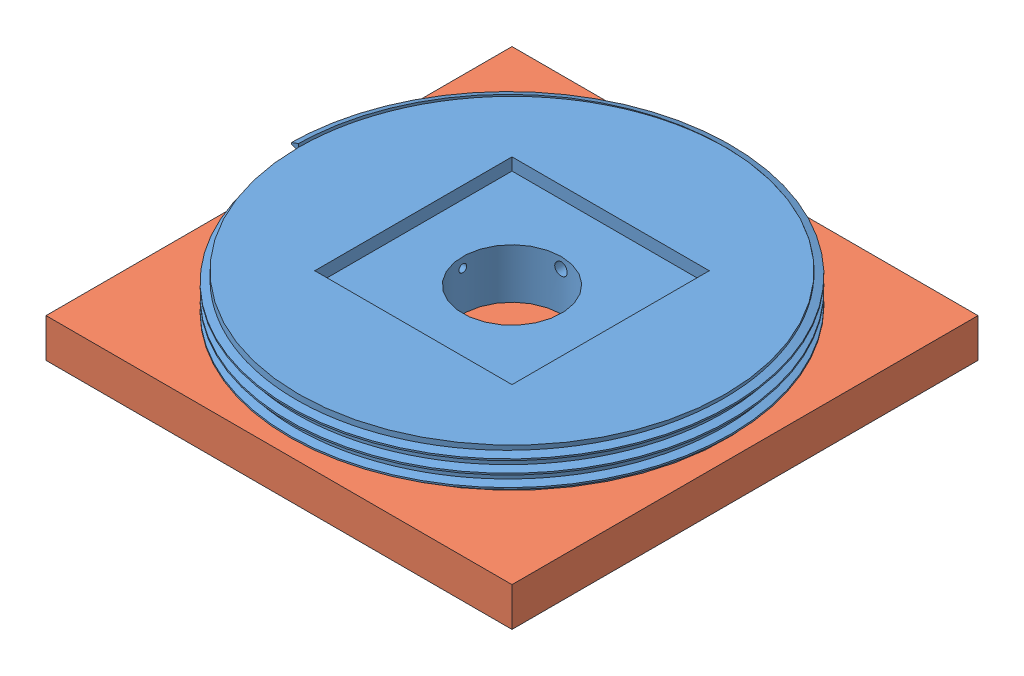
SolidWorks assembly ASIteration4, configuration Default. Lengths in mm.
Overall size (60 10.46 60).
2 component instances, 2 part files, 2 mates.
Components (placement in the parent):
- innerCircle-1: innerCircle [Default] at (0 2.7806 0) x (1 0 0.000011) z (-0.000011 0 1) size (56.85 8.86 56.84)
- Bottom-1: Bottom [Default] at (0 2.7806 0) x (0.000011 0 -1) z (0 1 0) size (60 60 10.46)
Mates (geometry in assembly coordinates):
- Coincident2: coincident anti-aligned: line of innerCircle-1 through (8 0 10.7806) axis (0 0 -1); line of Bottom-1 through (10 0 0.7806) axis (0 0 1)
- Screw1: screw = 0.625 aligned: cylinder of innerCircle-1 through (0 10.7806 0) axis (0 -1 0) radius 27.5; cylinder of Bottom-1 through (0 10.7806 0) axis (0 -1 0) radius 27.55
